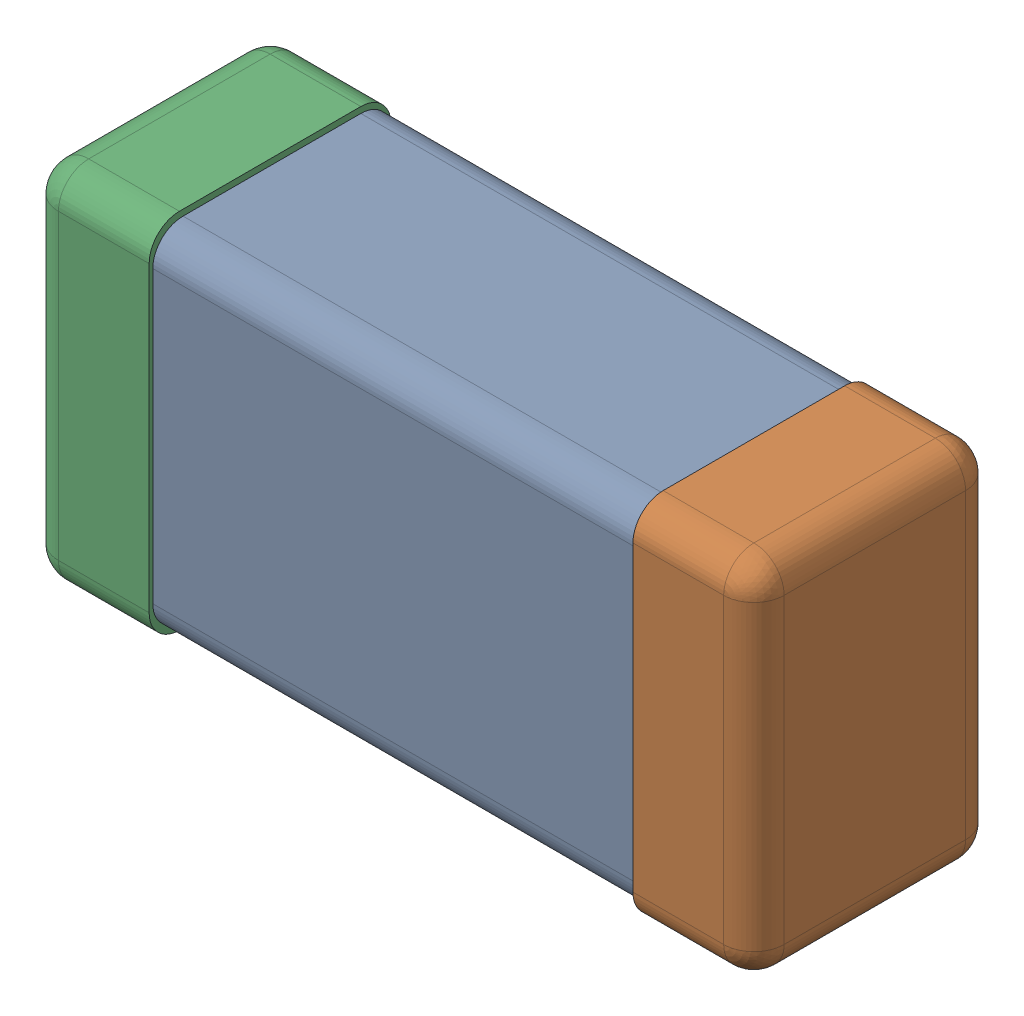
SolidWorks assembly C0201_020_19, configuration Standard. Lengths in mm.
Overall size (0.6 0.3 0.2).
3 component instances, 3 part files, 0 mates.
Components (placement in the parent):
- Part 3_2-1: Part 3_2 [Standard] at (0 0 -7.3015) size (0.5 0.29 0.2)
- Part 2_2-1: Part 2_2 [Standard] at (0 0 -7.3) size (0.1 0.3 0.2)
- Part 1_2-1: Part 1_2 [Standard] at (0 0 -7.3) size (0.1 0.3 0.2)
